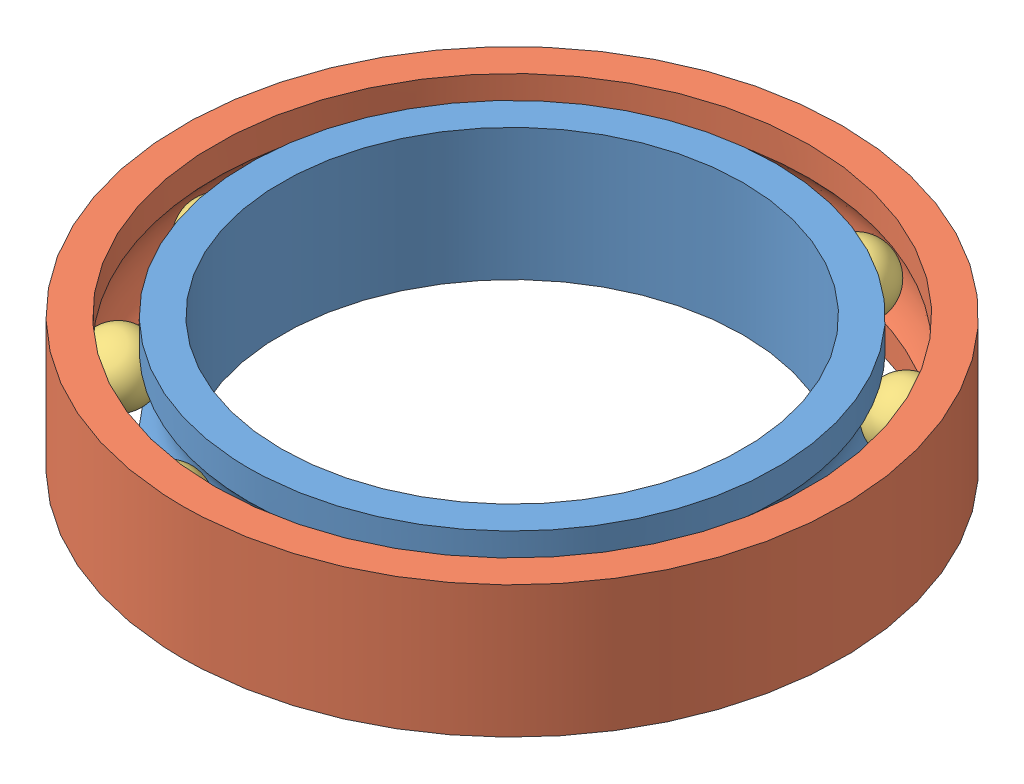
SolidWorks assembly Сборка1, configuration По умолчанию. Lengths in mm.
Overall size (10 2 10).
12 component instances, 3 part files, 3 mates.
Components (placement in the parent):
- Вн_кольцо-1: Вн_кольцо [По умолчанию] at origin size (8 2 8)
- Нар_кольцо-2: Нар_кольцо [По умолчанию] at origin size (10 2 10)
- Шарик-1: Шарик [По умолчанию] at (-4.245 0 0.2067) size (1 1 1)
- Шарик-2: Шарик [По умолчанию] at (-3.5558 0 -2.3279) x (0.809017 0 0.587785) z (-0.587785 0 0.809017) size (1 1 1)
- Шарик-3: Шарик [По умолчанию] at (-1.5084 0 -3.9733) x (0.309017 0 0.951057) z (-0.951057 0 0.309017) size (1 1 1)
- Шарик-4: Шарик [По умолчанию] at (1.1151 0 -4.1011) x (-0.309017 0 0.951057) z (-0.951057 0 -0.309017) size (1 1 1)
- Шарик-5: Шарик [По умолчанию] at (3.3127 0 -2.6624) x (-0.809017 0 0.587785) z (-0.587785 0 -0.809017) size (1 1 1)
- Шарик-6: Шарик [По умолчанию] at (4.245 0 -0.2067) x (-1 0 0) z (0 0 -1) size (1 1 1)
- Шарик-7: Шарик [По умолчанию] at (3.5558 0 2.3279) x (-0.809017 0 -0.587785) z (0.587785 0 -0.809017) size (1 1 1)
- Шарик-8: Шарик [По умолчанию] at (1.5084 0 3.9733) x (-0.309017 0 -0.951057) z (0.951057 0 -0.309017) size (1 1 1)
- Шарик-9: Шарик [По умолчанию] at (-1.1151 0 4.1011) x (0.309017 0 -0.951057) z (0.951057 0 0.309017) size (1 1 1)
- Шарик-10: Шарик [По умолчанию] at (-3.3127 0 2.6624) x (0.809017 0 -0.587785) z (0.587785 0 0.809017) size (1 1 1)
Mates (geometry in assembly coordinates):
- Концентричный1: concentric aligned: cylinder of Вн_кольцо-1 through (0 1 0) axis (0 -1 0) radius 4; cylinder of Нар_кольцо-2 through (0 1 0) axis (0 -1 0) radius 4.5
- Совпадение1: coincident aligned: plane of Вн_кольцо-1 through (0 0 0) normal (0 1 0); plane of Нар_кольцо-2 through (0 0 0) normal (0 1 0)
- Совпадение2: coincident: point of Шарик-1; circle of assembly
